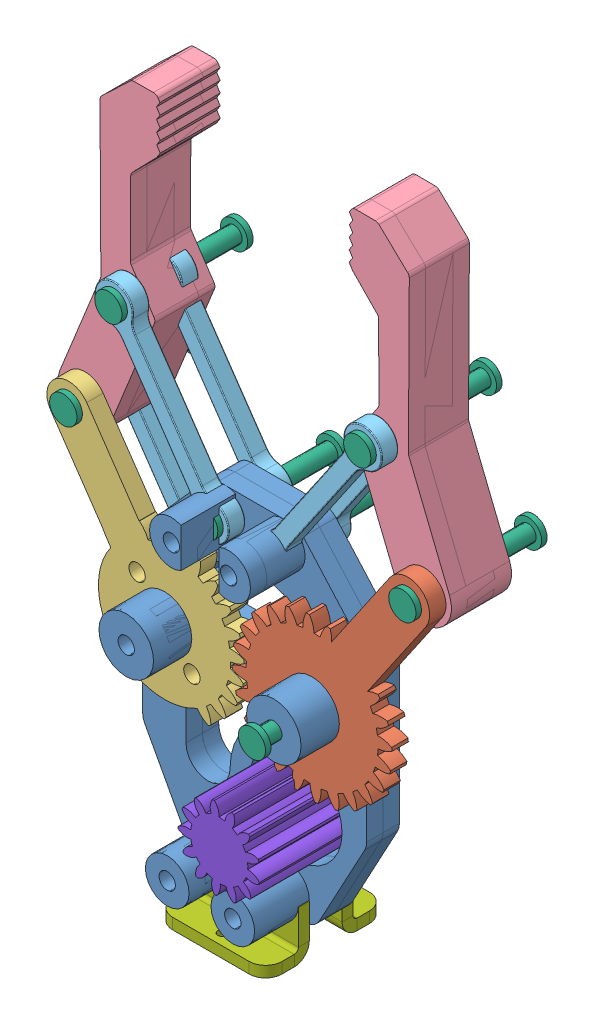
SolidWorks assembly Assem6, configuration Default. Lengths in mm.
Overall size (95 125.62 34).
25 component instances, 8 part files, 47 mates.
Components (placement in the parent):
- Part3-3-1: Part3-3 [Default] at origin size (41 62 13)
- part4-4-1: part4-4 [Default] at (13.5 37.5997 3) x (0 0 1) z (-0.565431 -0.824796 0) size (3 29.07 49.54)
- part5-5-1: part5-5 [Default] at (-13.5 37.5997 6) x (0 0 -1) z (0.668251 -0.743936 0) size (3 26.63 49.27)
- Part1-1-1: Part1-1 [Default] at (-31.0284 63.1684 -5) x (0.375052 0.927004 0) z (0 0 1) size (60.3 20.75 8)
- Part2-2-1: Part2-2 [Default] at (-5.2398 58 4.5) x (-0.565723 0.824596 0) z (0 0 1) size (38 7 3)
- Part2-2-2: Part2-2 [Default] at (5.2398 58 4.5) x (0.565723 0.824596 0) z (0 0 1) size (38 7 3)
- Part1-1-2: Part1-1 [Default] at (31.0284 63.1684 3) x (-0.375052 0.927004 0) z (0 0 -1) size (60.3 20.75 8)
- Part3-3-2: Part3-3 [Default] at (0 0 -3) size (41 62 13)
- Part1-1-3: Part1-1 [Default] at (31.0284 63.1684 0) x (-0.375052 0.927004 0) z (0 0 -1) size (60.3 20.75 8)
- Part1-1-4: Part1-1 [Default] at (-31.0284 63.1684 -8) x (0.375052 0.927004 0) z (0 0 1) size (60.3 20.75 8)
- Part2-2-5: Part2-2 [Default] at (-5.2398 58 -4.5) x (-0.565723 0.824596 0) z (0 0 1) size (38 7 3)
- Part2-2-6: Part2-2 [Default] at (5.2398 58 -4.5) x (0.565723 0.824596 0) z (0 0 1) size (38 7 3)
- Part2-2-9: Part2-2 [Default] at (13.5 37.5997 -4.5) x (0.565431 0.824796 0) z (0 0 1) size (38 7 3)
- Part2-2-10: Part2-2 [Default] at (-13.5 37.5997 -4.5) x (-0.565431 0.824796 0) z (0 0 1) size (38 7 3)
- Part6-6-1: Part6-6 [Default] at (13.5 37.5997 17) x (1 0 0) z (0 1 0) size (5 24 5)
- Part7-7-1: Part7-7 [Default] at (0 -5.279 3) x (0 -1 0) z (-1 0 0) size (12 8 20)
- Part6-6-2: Part6-6 [Default] at (-13.5 37.5997 -17) x (-0.923728 -0.383049 0) z (-0.383049 0.923728 0) size (5 24 5)
- Part6-6-3: Part6-6 [Default] at (-31.0284 63.1684 -17) x (-0.923728 -0.383049 0) z (-0.383049 0.923728 0) size (5 24 5)
- Part6-6-4: Part6-6 [Default] at (-5.2398 58 -17) x (0.923728 0.383049 0) z (0.383049 -0.923728 0) size (5 24 5)
- Part6-6-5: Part6-6 [Default] at (-22.7772 83.5625 -17) x (0.923728 0.383049 0) z (0.383049 -0.923728 0) size (5 24 5)
- Part6-6-6: Part6-6 [Default] at (22.7772 83.5625 -17) x (0.923728 0.383049 0) z (0.383049 -0.923728 0) size (5 24 5)
- Part6-6-7: Part6-6 [Default] at (5.2398 58 -17) x (0.923728 0.383049 0) z (0.383049 -0.923728 0) size (5 24 5)
- Part6-6-8: Part6-6 [Default] at (31.0284 63.1684 -17) x (0.923728 0.383049 0) z (0.383049 -0.923728 0) size (5 24 5)
- Part7-7-3: Part7-7 [Default] at (0 -5.279 -3) x (0 -1 0) z (1 0 0) size (12 8 20)
- part8-8-1: part8-8 [Default] at (7.5 17.5997 7) x (0 0 -1) z (0.835413 -0.549623 0) size (23 17.5 17.5)
Mates (geometry in assembly coordinates):
- Concentric1: concentric aligned: cylinder of Part3-3-1 through (13.5 37.5997 3) axis (0 0 -1) radius 1.5; cylinder of part4-4-1 through (13.5 37.5997 53.0001) axis (0 0 -1) radius 1.5
- Coincident1: coincident anti-aligned: plane of Part3-3-1 through (0 0 3) normal (0 0 1); plane of part4-4-1 through (13.5 37.5997 3) normal (0 0 -1)
- Concentric2: concentric anti-aligned: cylinder of Part3-3-1 through (-13.5 37.5997 3) axis (0 0 -1) radius 1.5; cylinder of part5-5-1 through (-13.5 37.5997 -44.0001) axis (0 0 1) radius 1.5
- Coincident3: coincident anti-aligned: plane of Part3-3-1 through (0 0 3) normal (0 0 1); plane of part5-5-1 through (-13.5 37.5997 3) normal (0 0 -1)
- Concentric3: concentric aligned: cylinder of Part3-3-1 through (-5.2398 58 3) axis (0 0 -1) radius 1.5; cylinder of Part2-2-1 through (-5.2398 58 6) axis (0 0 -1) radius 1.5
- Coincident4: coincident anti-aligned: plane of Part3-3-1 through (0 0 3) normal (0 0 1); plane of Part2-2-1 through (-5.2398 58 3) normal (0 0 -1)
- Concentric4: concentric anti-aligned: cylinder of part5-5-1 through (-31.0284 63.1684 3) axis (0 0 1) radius 1.5; cylinder of Part1-1-1 through (-31.0284 63.1684 3) axis (0 0 -1) radius 1.5
- Concentric5: concentric aligned: cylinder of Part1-1-1 through (-22.7772 83.5625 3) axis (0 0 -1) radius 1.5; cylinder of Part2-2-1 through (-22.7772 83.5625 6) axis (0 0 -1) radius 1.5
- Concentric6: concentric anti-aligned: cylinder of part4-4-1 through (31.0284 63.1684 6) axis (0 0 -1) radius 1.5; cylinder of Part1-1-2 through (31.0284 63.1684 -5) axis (0 0 1) radius 1.5
- Concentric7: concentric aligned: cylinder of Part3-3-1 through (5.2398 58 3) axis (0 0 -1) radius 1.5; cylinder of Part2-2-2 through (5.2398 58 6) axis (0 0 -1) radius 1.5
- Concentric8: concentric anti-aligned: cylinder of Part2-2-2 through (22.7772 83.5625 6) axis (0 0 -1) radius 1.5; cylinder of Part1-1-2 through (22.7772 83.5625 -5) axis (0 0 1) radius 1.5
- Coincident8: coincident anti-aligned: plane of part4-4-1 through (13.5 37.5997 3) normal (0 0 -1); plane of Part1-1-2 through (31.0284 63.1684 3) normal (0 0 1)
- Coincident9: coincident anti-aligned: plane of part5-5-1 through (-13.5 37.5997 3) normal (0 0 -1); plane of Part1-1-1 through (-31.0284 63.1684 3) normal (0 0 1)
- Coincident10: coincident anti-aligned: plane of Part3-3-1 through (0 0 3) normal (0 0 1); plane of Part2-2-2 through (5.2398 58 3) normal (0 0 -1)
- Concentric11: concentric aligned: cylinder of Part3-3-2 through (13.5 37.5997 0) axis (0 0 -1) radius 1.5; cylinder of Part2-2-9 through (13.5 37.5997 -3) axis (0 0 -1) radius 1.5
- Concentric12: concentric anti-aligned: cylinder of Part1-1-3 through (31.0284 63.1684 -8) axis (0 0 1) radius 1.5; cylinder of Part2-2-9 through (31.0284 63.1684 -3) axis (0 0 -1) radius 1.5
- Coincident11: coincident anti-aligned: plane of Part3-3-2 through (0 0 -3) normal (0 0 -1); plane of Part2-2-9 through (13.5 37.5997 -3) normal (0 0 1)
- Concentric13: concentric aligned: cylinder of Part3-3-2 through (-13.5 37.5997 0) axis (0 0 -1) radius 1.5; cylinder of Part2-2-10 through (-13.5 37.5997 -3) axis (0 0 -1) radius 1.5
- Concentric14: concentric aligned: cylinder of Part1-1-4 through (-31.0284 63.1684 0) axis (0 0 -1) radius 1.5; cylinder of Part2-2-10 through (-31.0284 63.1684 -3) axis (0 0 -1) radius 1.5
- Coincident12: coincident anti-aligned: plane of Part3-3-2 through (0 0 -3) normal (0 0 -1); plane of Part2-2-10 through (-13.5 37.5997 -3) normal (0 0 1)
- Concentric15: concentric: cylinder of part4-4-1 through (13.5 37.5997 53.0001) axis (0 0 -1) radius 1.5; cylinder of Part6-6-1 through (13.5 37.5997 17) axis (0 0 1) radius 1.5
- Coincident15: coincident anti-aligned: plane of Part2-2-9 through (13.5 37.5997 -6) normal (0 0 -1); plane of Part6-6-1 through (11 37.5997 -6) normal (0 0 1)
- Coincident16: coincident anti-aligned: plane of Part3-3-1 through (0 0 3) normal (0 0 1); plane of Part7-7-1 through (-10 -5.279 3) normal (0 0 -1)
- Concentric16: concentric: cylinder of Part3-3-1 through (-6 4 3) axis (0 0 -1) radius 1.5; cylinder of Part7-7-1 through (-6 4 3) axis (0 0 1) radius 1.5
- Concentric17: concentric anti-aligned: cylinder of Part3-3-1 through (6 4 3) axis (0 0 -1) radius 1.5; cylinder of Part7-7-1 through (6 4 3) axis (0 0 1) radius 1.5
- Concentric18: concentric anti-aligned: cylinder of part5-5-1 through (-13.5 37.5997 -44.0001) axis (0 0 1) radius 1.5; cylinder of Part6-6-2 through (-13.5 37.5997 -17) axis (0 0 -1) radius 1.5
- Coincident17: coincident anti-aligned: plane of part5-5-1 through (-13.5 37.5997 6) normal (0 0 1); plane of Part6-6-2 through (-11.1907 38.5573 6) normal (0 0 -1)
- Concentric19: concentric: cylinder of part5-5-1 through (-31.0284 63.1684 3) axis (0 0 1) radius 1.5; cylinder of Part6-6-3 through (-31.0284 63.1684 -17) axis (0 0 -1) radius 1.5
- Coincident18: coincident anti-aligned: plane of part5-5-1 through (-13.5 37.5997 6) normal (0 0 1); plane of Part6-6-3 through (-28.719 64.126 6) normal (0 0 -1)
- Concentric20: concentric aligned: cylinder of Part2-2-1 through (-5.2398 58 6) axis (0 0 -1) radius 1.5; cylinder of Part6-6-4 through (-5.2398 58 -17) axis (0 0 -1) radius 1.5
- Coincident19: coincident: plane of Part2-2-1 through (-5.2398 58 6) normal (0 0 1); plane of Part6-6-4 through (-7.5491 57.0424 6) normal (0 0 -1)
- Concentric21: concentric aligned: cylinder of Part2-2-1 through (-22.7772 83.5625 6) axis (0 0 -1) radius 1.5; cylinder of Part6-6-5 through (-22.7772 83.5625 -17) axis (0 0 -1) radius 1.5
- Coincident20: coincident: plane of Part2-2-1 through (-5.2398 58 6) normal (0 0 1); plane of Part6-6-5 through (-25.0865 82.6048 6) normal (0 0 -1)
- Concentric22: concentric aligned: cylinder of Part2-2-2 through (22.7772 83.5625 6) axis (0 0 -1) radius 1.5; cylinder of Part6-6-6 through (22.7772 83.5625 -17) axis (0 0 -1) radius 1.5
- Coincident21: coincident anti-aligned: plane of Part2-2-2 through (5.2398 58 6) normal (0 0 1); plane of Part6-6-6 through (20.4679 82.6048 6) normal (0 0 -1)
- Concentric23: concentric aligned: cylinder of Part2-2-2 through (5.2398 58 6) axis (0 0 -1) radius 1.5; cylinder of Part6-6-7 through (5.2398 58 -17) axis (0 0 -1) radius 1.5
- Coincident22: coincident anti-aligned: plane of Part2-2-2 through (5.2398 58 6) normal (0 0 1); plane of Part6-6-7 through (2.9305 57.0424 6) normal (0 0 -1)
- Concentric24: concentric aligned: cylinder of part4-4-1 through (31.0284 63.1684 6) axis (0 0 -1) radius 1.5; cylinder of Part6-6-8 through (31.0284 63.1684 -17) axis (0 0 -1) radius 1.5
- Coincident23: coincident anti-aligned: plane of part4-4-1 through (13.5 37.5997 6) normal (0 0 1); plane of Part6-6-8 through (28.719 62.2108 6) normal (0 0 -1)
- Coincident25: coincident anti-aligned: plane of Part3-3-2 through (0 0 -3) normal (0 0 -1); plane of Part7-7-3 through (10 -5.279 -3) normal (0 0 1)
- Concentric27: concentric aligned: cylinder of Part3-3-2 through (6 4 0) axis (0 0 -1) radius 1.5; cylinder of Part7-7-3 through (6 4 -3) axis (0 0 -1) radius 1.5
- Concentric28: concentric aligned: cylinder of Part3-3-2 through (-6 4 0) axis (0 0 -1) radius 1.5; cylinder of Part7-7-3 through (-6 4 -3) axis (0 0 -1) radius 1.5
- Concentric29: concentric anti-aligned: cylinder of Part3-3-1 through (7.5 17.5997 3) axis (0 0 -1) radius 8.5; cylinder of part8-8-1 through (7.5 17.5997 -6) axis (0 0 1) radius 8.75
- Coincident26: coincident anti-aligned: plane of Part3-3-2 through (0 0 -3) normal (0 0 -1); plane of part8-8-1 through (7.5 17.5997 -3) normal (0 0 1)
- LimitAngle1: limit planar angle = 2.540637 rad anti-aligned: plane of part5-5-1 through (-16.7992 35.338 3) normal (-0.824796 -0.565431 0); plane of Part3-3-1 through (-20.5 47.8997 3) normal (-1 0 0)
- GearMate1: gear = 1 : 1 mm: cylinder of part5-5-1 through (-13.5 37.5997 3) axis (0 0 1) radius 12.0927; cylinder of part4-4-1 through (13.5 37.5997 6) axis (0 0 -1) radius 12.0927
- GearMate2: gear = 13 : 24 mm: cylinder of part8-8-1 through (7.5 17.5997 7) axis (0 0 1) radius 5.249; cylinder of part4-4-1 through (13.5 37.5997 6) axis (0 0 -1) radius 12.0927
